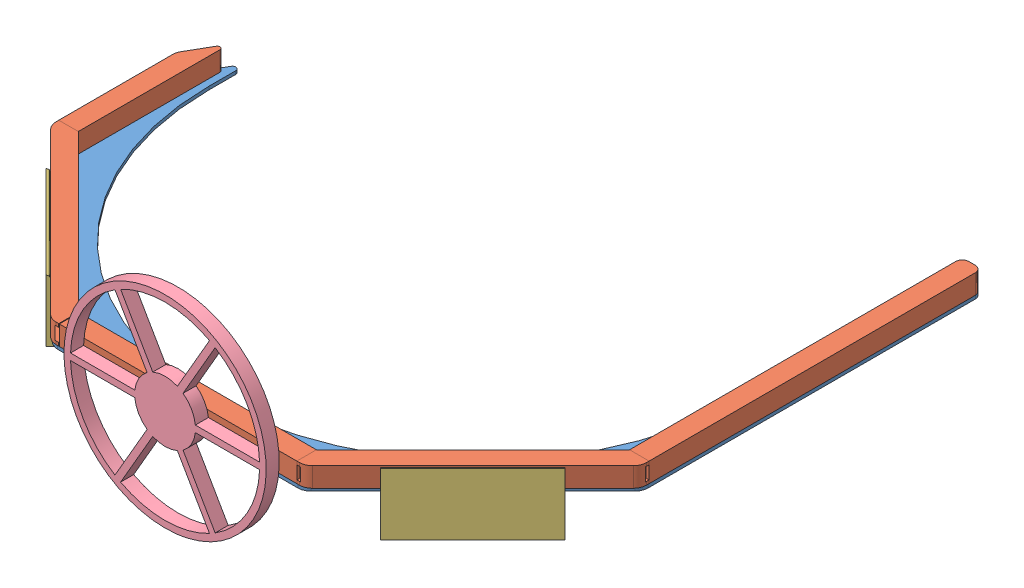
SolidWorks assembly recycling_rotate_asm, configuration Default. Lengths in mm.
Overall size (582.57 228.04 508).
10 component instances, 4 part files, 0 mates.
Components (placement in the parent):
- recycling_rotate_weldment-1: recycling_rotate_weldment [Default] at origin size (582.57 228.04 508)
  - recycling_rotate_plate-1: recycling_rotate_plate [Default] at origin size (574.68 3.17 495.3)
  - recycling_rotate_tube-16: recycling_rotate_tube [-2] at (-115.2525 12.7 282.575) x (0 0 -1) z (1 0 0) size (19.05 19.05 231.14)
  - recycling_rotate_tube-1: recycling_rotate_tube [Default] at (277.8125 12.7 120.65) x (-1 0 0) z (0 0 -1) size (19.05 19.05 323.85)
  - recycling_rotate_tube-14: recycling_rotate_tube [-3] at (-277.8125 12.7 -463.55) size (19.05 19.05 140.36)
  - recycling_rotate_tube-17: recycling_rotate_tube [-4] at (14.5071 12.7 387.9008) x (-0.707107 0 -0.707107) z (0.707107 0 -0.707107) size (19.05 19.05 242.47)
  - recycling_rotate_tube-18: recycling_rotate_tube [-4] at (-14.5071 12.7 387.9008) x (0.707107 0 -0.707107) z (-0.707107 0 -0.707107) size (19.05 19.05 242.47)
  - recycling_rotate_l-angle-1: recycling_rotate_l-angle [PreviewCfg] at (207.8029 -38.1 212.5654) x (-0.707107 0 -0.707107) z (0.707107 0 -0.707107) size (34.92 60.32 127)
  - recycling_rotate_l-angle-2: recycling_rotate_l-angle [PreviewCfg] at (-207.8029 -38.1 212.5654) x (0.707107 0 -0.707107) z (0.707107 0 0.707107) size (34.92 60.32 127)
  - recycling_rotate_wheel-1: recycling_rotate_wheel [Default] at (0.3175 12.7 292.1) x (0.984808 0.173648 0) z (0.173648 -0.984808 0) size (196.85 12.7 196.85)
